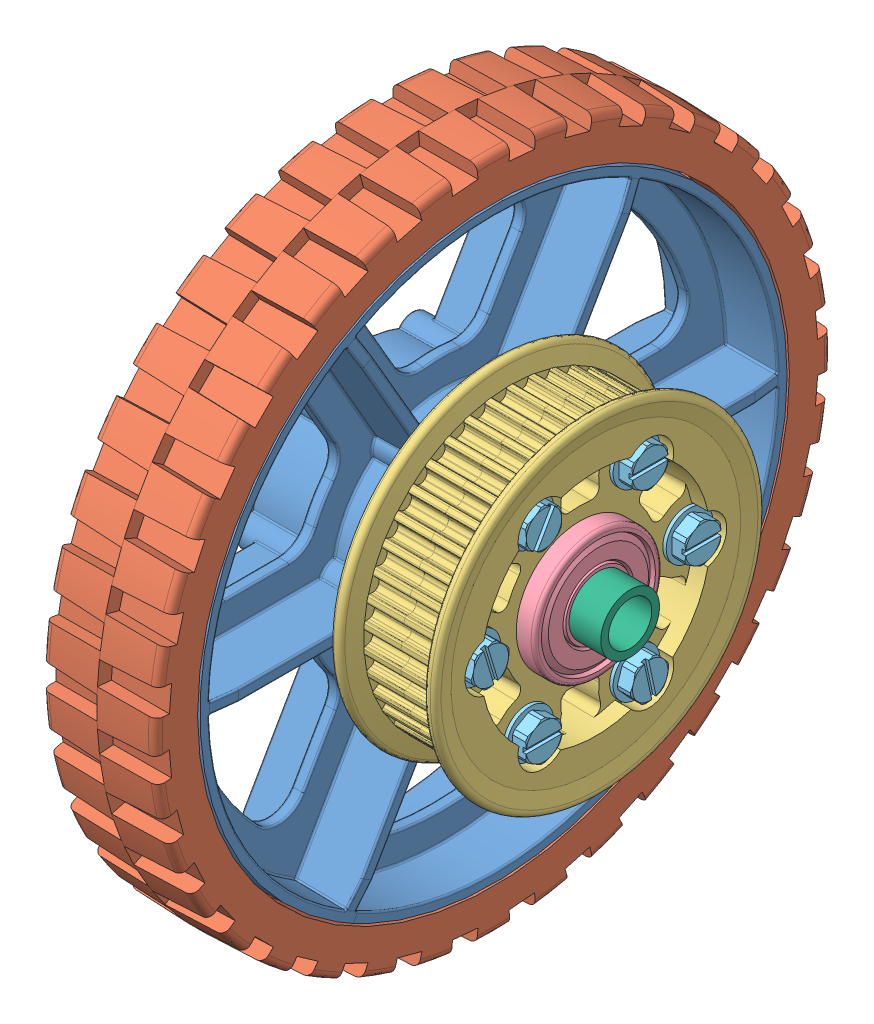
SolidWorks assembly Wheel HiGrip 6 in - Bearings, Pulleys, Spacers, configuration Default. Lengths in mm.
Overall size (85.56 152.4 152.4).
15 component instances, 7 part files, 26 mates.
Components (placement in the parent):
- Wheel HiGrip 6 in-1: Wheel HiGrip 6 in [Default] at (83.7987 67.439 110.9939) size (35.05 152.4 152.4)
  - Wheel HiGrip 6 in_Wheel-1: Wheel HiGrip 6 in_Wheel [Default] at (-52.6446 9.4231 21.378) size (35.05 132.08 132.08)
  - Wheel HiGrip 6 in_Tread-1: Wheel HiGrip 6 in_Tread [Default] at (-65.3446 9.4231 21.378) x (0 0 -1) z (1 0 0) size (152.4 152.4 25.58)
- Half Pulley 42t 5 mm HTD-1: Half Pulley 42t 5 mm HTD [Default] at (47.6006 76.862 132.3719) x (1 0 0) z (0 -0.5 0.866025) size (13 74.23 74.23)
- Half Pulley 42t 5 mm HTD-2: Half Pulley 42t 5 mm HTD [Default] at (64.263 76.862 132.3719) x (-1 0 0) z (0 -0.499927 0.866067) size (13 74.23 74.23)
- Bearing 1614ZZ-1: Bearing 1614ZZ [Default] at (62.612 76.862 132.3719) x (0 -0.157148 -0.987575) z (-1 0 0) size (28.57 28.57 9.53)
- Bearing 1614ZZ-2: Bearing 1614ZZ [Default] at (15.2791 76.862 132.3719) x (0 0 -1) z (1 0 0) size (28.57 28.57 9.53)
- 10-24 x 1.25 in Thread Forming Screw-1: 10-24 x 1.25 in Thread Forming Screw [93882A213] at (63.247 76.8605 108.5602) x (0 0 -1) z (1 0 0) size (10.52 10.52 35.59)
- 10-24 x 1.25 in Thread Forming Screw-2: 10-24 x 1.25 in Thread Forming Screw [93882A213] at (63.247 97.4833 120.4656) x (0 0 -1) z (1 0 0) size (10.52 10.52 35.59)
- 10-24 x 1.25 in Thread Forming Screw-3: 10-24 x 1.25 in Thread Forming Screw [93882A213] at (63.247 56.2398 144.2799) x (0 0 -1) z (1 0 0) size (10.52 10.52 35.59)
- 10-24 x 1.25 in Thread Forming Screw-4: 10-24 x 1.25 in Thread Forming Screw [93882A213] at (63.247 76.8625 156.1852) x (0 -0.95788 -0.287168) z (1 0 0) size (10.52 10.52 35.59)
- 10-24 x 1.25 in Thread Forming Screw-5: 10-24 x 1.25 in Thread Forming Screw [93882A213] at (63.247 97.4843 144.2781) x (0 -0.868976 0.494854) z (1 0 0) size (10.52 10.52 35.59)
- 10-24 x 1.25 in Thread Forming Screw-6: 10-24 x 1.25 in Thread Forming Screw [93882A213] at (63.247 56.2388 120.4674) x (0 -0.977348 -0.211637) z (1 0 0) size (10.52 10.52 35.59)
- Spacer 0.28 in x 0.382 ID-1: Spacer 0.28 in x 0.382 ID [Default] at (74.4865 76.862 132.3719) x (0 -0.35357 0.935408) z (-1 0 0) size (13.16 13.16 7.11)
- Spacer 0.85 in x 0.38 ID-1: Spacer 0.85 in x 0.38 ID [Default] at (-11.0734 76.862 132.3719) x (0 0 -1) z (1 0 0) size (19.05 19.05 21.59)
Mates (geometry in assembly coordinates):
- Concentric1: concentric anti-aligned: cylinder of Wheel HiGrip 6 in-1/Wheel HiGrip 6 in_Wheel-1 through (42.2666 76.862 132.3719) axis (1 0 0) radius 14.2875; cylinder of Half Pulley 42t 5 mm HTD-1 through (54.0141 76.862 132.3719) axis (-1 0 0) radius 14.2875
- Coincident1: coincident anti-aligned: plane of Wheel HiGrip 6 in-1/Wheel HiGrip 6 in_Wheel-1 through (48.6166 76.862 132.3719) normal (1 0 0); plane of Half Pulley 42t 5 mm HTD-1 through (48.6166 76.862 132.3719) normal (-1 0 0)
- Concentric4: concentric aligned: cylinder of Half Pulley 42t 5 mm HTD-1 through (57.2018 56.2388 120.4674) axis (-1 0 0) radius 4.1275; cylinder of Half Pulley 42t 5 mm HTD-2 through (57.3288 56.2388 120.4674) axis (-1 0 0) radius 4.1529
- Concentric5: concentric aligned: circle of Half Pulley 42t 5 mm HTD-1; cylinder of Half Pulley 42t 5 mm HTD-2 through (54.6618 97.4843 144.2781) axis (1 0 0) radius 4.1275
- Coincident2: coincident anti-aligned: plane of Half Pulley 42t 5 mm HTD-1 through (55.9318 104.6844 148.5781) normal (1 0 0); plane of Half Pulley 42t 5 mm HTD-2 through (55.9318 48.9145 116.3824) normal (-1 0 0)
- Concentric6: concentric anti-aligned: cylinder of Half Pulley 42t 5 mm HTD-2 through (57.8495 76.862 132.3719) axis (1 0 0) radius 14.2875; cylinder of Bearing 1614ZZ-1 through (62.612 76.862 132.3719) axis (-1 0 0) radius 4.7625
- Concentric7: concentric anti-aligned: cylinder of Wheel HiGrip 6 in-1/Wheel HiGrip 6 in_Wheel-1 through (20.0416 76.862 132.3719) axis (-1 0 0) radius 14.2875; cylinder of Bearing 1614ZZ-2 through (15.2791 76.862 132.3719) axis (1 0 0) radius 4.7625
- Coincident3: coincident anti-aligned: plane of Wheel HiGrip 6 in-1/Wheel HiGrip 6 in_Wheel-1 through (20.0416 76.862 132.3719) normal (-1 0 0); plane of Bearing 1614ZZ-2 through (20.0416 76.862 132.3719) normal (1 0 0)
- Coincident4: coincident anti-aligned: plane of Half Pulley 42t 5 mm HTD-2 through (57.8495 76.862 132.3719) normal (1 0 0); plane of Bearing 1614ZZ-1 through (57.8495 76.862 132.3719) normal (-1 0 0)
- Concentric8: concentric anti-aligned: cylinder of Half Pulley 42t 5 mm HTD-2 through (55.9318 97.4833 120.4656) axis (1 0 0) radius 2.54; cylinder of 10-24 x 1.25 in Thread Forming Screw-2 through (64.0141 97.4833 120.4656) axis (-1 0 0) radius 5.2578
- Concentric9: concentric anti-aligned: cylinder of Half Pulley 42t 5 mm HTD-2 through (55.9318 76.8605 108.5602) axis (1 0 0) radius 2.54; circle of 10-24 x 1.25 in Thread Forming Screw-1
- Concentric10: concentric anti-aligned: cylinder of Half Pulley 42t 5 mm HTD-2 through (55.9318 56.2388 120.4674) axis (1 0 0) radius 2.54; cylinder of 10-24 x 1.25 in Thread Forming Screw-6 through (64.0141 56.2388 120.4674) axis (-1 0 0) radius 5.2578
- Concentric11: concentric anti-aligned: cylinder of Half Pulley 42t 5 mm HTD-2 through (55.9318 56.2398 144.2799) axis (1 0 0) radius 2.54; circle of 10-24 x 1.25 in Thread Forming Screw-3
- Concentric12: concentric anti-aligned: cylinder of Half Pulley 42t 5 mm HTD-2 through (55.9318 76.8625 156.1852) axis (1 0 0) radius 2.54; circle of 10-24 x 1.25 in Thread Forming Screw-4
- Concentric13: concentric anti-aligned: cylinder of Half Pulley 42t 5 mm HTD-2 through (55.9318 97.4843 144.2781) axis (1 0 0) radius 2.54; circle of 10-24 x 1.25 in Thread Forming Screw-5
- Coincident5: coincident aligned: plane of 10-24 x 1.25 in Thread Forming Screw-4 through (67.0824 78.1785 151.7955) normal (1 0 0); plane of 10-24 x 1.25 in Thread Forming Screw-5 through (67.0824 95.2165 140.2958) normal (1 0 0)
- Coincident6: coincident aligned: plane of 10-24 x 1.25 in Thread Forming Screw-3 through (67.0824 60.8225 144.2799) normal (1 0 0); plane of 10-24 x 1.25 in Thread Forming Screw-4 through (67.0824 78.1785 151.7955) normal (1 0 0)
- Coincident7: coincident aligned: plane of 10-24 x 1.25 in Thread Forming Screw-3 through (67.0824 60.8225 144.2799) normal (1 0 0); plane of 10-24 x 1.25 in Thread Forming Screw-6 through (67.0824 57.2087 115.9884) normal (1 0 0)
- Coincident8: coincident aligned: plane of 10-24 x 1.25 in Thread Forming Screw-1 through (67.0824 81.4433 108.5602) normal (1 0 0); plane of 10-24 x 1.25 in Thread Forming Screw-6 through (67.0824 57.2087 115.9884) normal (1 0 0)
- Coincident9: coincident aligned: plane of 10-24 x 1.25 in Thread Forming Screw-1 through (67.0824 81.4433 108.5602) normal (1 0 0); plane of 10-24 x 1.25 in Thread Forming Screw-2 through (67.0824 102.066 120.4656) normal (1 0 0)
- Coincident10: coincident anti-aligned: plane of Half Pulley 42t 5 mm HTD-2 through (63.247 76.862 132.3719) normal (1 0 0); plane of 10-24 x 1.25 in Thread Forming Screw-5 through (63.247 95.2165 140.2958) normal (-1 0 0)
- Concentric14: concentric anti-aligned: cylinder of Bearing 1614ZZ-2 through (15.2791 76.862 132.3719) axis (1 0 0) radius 4.7625; cylinder of Spacer 0.85 in x 0.38 ID-1 through (10.5166 76.862 132.3719) axis (-1 0 0) radius 9.525
- Coincident11: coincident anti-aligned: plane of Bearing 1614ZZ-2 through (10.5166 76.862 132.3719) normal (-1 0 0); plane of Spacer 0.85 in x 0.38 ID-1 through (10.5166 76.862 132.3719) normal (1 0 0)
- Concentric15: concentric anti-aligned: cylinder of Bearing 1614ZZ-1 through (62.612 76.862 132.3719) axis (-1 0 0) radius 4.7625; cylinder of Spacer 0.28 in x 0.382 ID-1 through (67.3745 76.862 132.3719) axis (1 0 0) radius 4.8514
- Coincident12: coincident anti-aligned: plane of Bearing 1614ZZ-1 through (67.3745 76.862 132.3719) normal (1 0 0); plane of Spacer 0.28 in x 0.382 ID-1 through (67.3745 76.862 132.3719) normal (-1 0 0)
- Concentric16: concentric aligned: cylinder of Wheel HiGrip 6 in-1/Wheel HiGrip 6 in_Wheel-1 through (48.6166 97.4843 144.2781) axis (-1 0 0) radius 1.9939; cylinder of Half Pulley 42t 5 mm HTD-1 through (55.9318 97.4843 144.2781) axis (-1 0 0) radius 2.54
